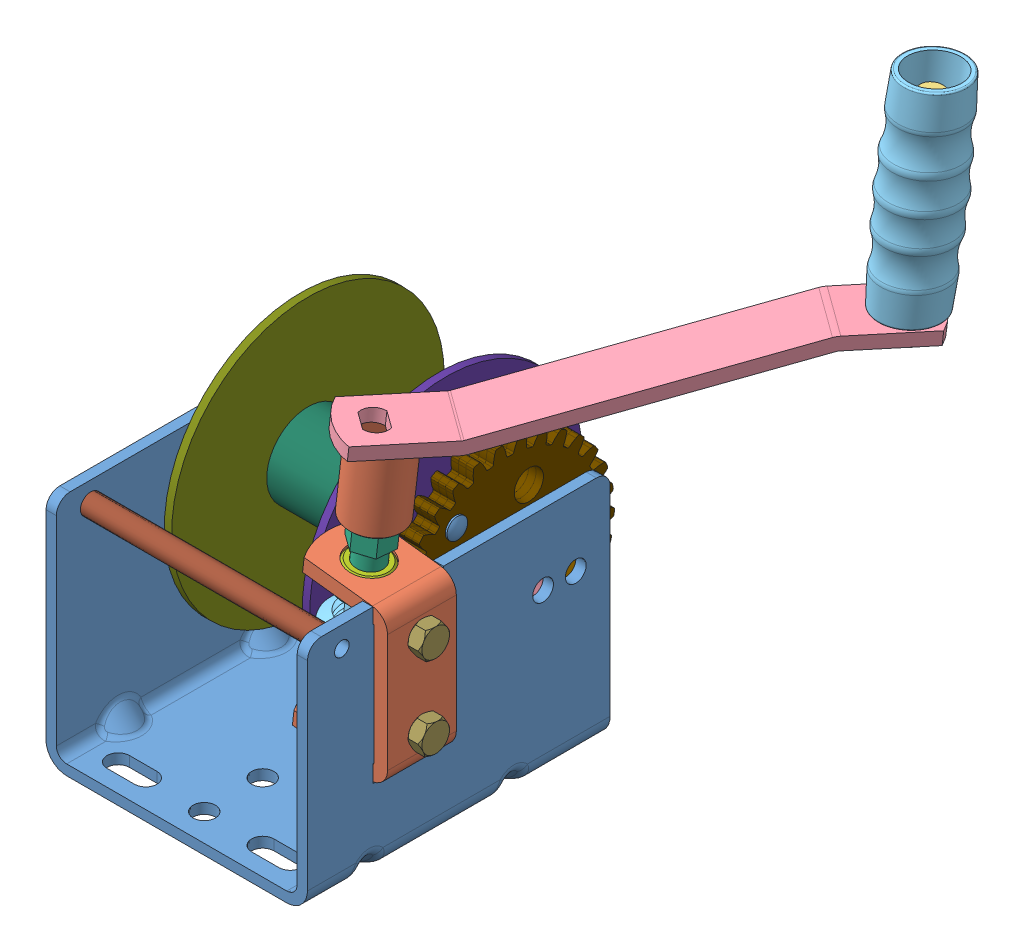
SolidWorks assembly WG1500 Hex Drive (1), configuration Predeterminado. Lengths in mm.
Overall size (251.67 346.34 225.75).
32 component instances, 24 part files, 0 mates.
Components (placement in the parent):
- 404458 Base-1: 404458 Base [Predeterminado] at origin size (120.73 107.99 139.7)
- 404457 Worm Bracket-1: 404457 Worm Bracket [Predeterminado] at (17.981 37.5729 93.2078) size (48.69 74.45 31.75)
- 204007 Drive Shaft Bottom Bushing-1: 204007 Drive Shaft Bottom Bushing [Predeterminado] at (34.0483 39.6265 93.2078) x (0.11696 0.993137 0) z (-0.289917 0.034143 -0.956443) size (10.32 23.81 23.81)
- 404439 Spacer-1: 404439 Spacer [Predeterminado] at (36.5475 60.8476 93.2078) x (-0.574047 0.067604 0.816027) z (-0.11696 -0.993137 0) size (22.23 22.23 11.05)
- 404435 Worm Gear P8-1: 404435 Worm Gear P8 [Predeterminado] at (36.5475 60.8476 93.2078) x (-0.989929 0.116582 -0.080302) z (0.11696 0.993137 0) size (33.45 33.52 39.41)
- 205186 Thrust Bearing Race-1: 205186 Thrust Bearing Race [Predeterminado] at (41.0963 99.4731 93.2078) x (0.864285 -0.101785 0.492597) z (-0.11696 -0.993137 0) size (23.81 23.81 0.79)
- 204006 Drive Shaft Bushing-1: 204006 Drive Shaft Bushing [Predeterminado] at (42.2863 109.777 93.2078) x (-0.11696 -0.993137 0) z (-0.992861 0.116927 0.023576) size (8.69 23.81 23.81)
- 205109 Flat Washer-1: 205109 Flat Washer [Predeterminado] at (41.2696 101.1436 93.2078) x (0.992132 -0.116841 -0.044969) z (-0.11696 -0.993137 0) size (23.81 23.81 1.19)
- 204489 Spring Washer-1: 204489 Spring Washer [Predeterminado] at (41.1255 99.9201 93.2078) x (0.992772 -0.116917 0.027098) z (-0.11696 -0.993137 0) size (19.05 19.05 0.41)
- 205246 Roll Pin-1: 205246 Roll Pin [Predeterminado] at (50.6614 92.7533 94.0365) x (0.122809 0.425097 -0.896778) z (-0.989929 0.116582 -0.080302) size (4.76 4.76 20.64)
- 404434 Base spacer-1: 404434 Base spacer [Predeterminado] at (0 98.425 123.825) x (0 0.855839 -0.517243) z (-1 0 0) size (9.53 9.53 111.12)
- 205235 Screw-1: 205235 Screw [Predeterminado] at (66.675 91.929 93.2078) x (0 0.999629 0.027237) z (1 0 0) size (14.68 14.68 20.87)
- 205235 Screw-2: 205235 Screw [Predeterminado] at (66.675 53.8289 93.2078) x (0 -0.575948 -0.817487) z (1 0 0) size (14.68 14.68 20.87)
- 204808 Spacer-1: 204808 Spacer [Predeterminado] at (-55.5625 75.4062 30.9626) x (0 0 -1) z (1 0 0) size (12.55 12.55 111.12)
- 204803 Lock Nut-1: 204803 Lock Nut [Predeterminado] at (-66.675 75.4062 30.9626) x (0 -0.583557 -0.812072) z (1 0 0) size (14.68 14.68 8.37)
- 304432 Reel Assembly-1: 304432 Reel Assembly [Predeterminado] at (-54.9275 75.4062 30.9626) x (1 0 0) z (0 0.563677 0.825995) size (109.98 162.45 162.45)
  - 406042 Large Reel Hub-1: 406042 Large Reel Hub [Predeterminado] at origin size (109.98 38.1 38.1)
  - 404440 Side Plate-1: 404440 Side Plate [Predeterminado] at (3.3274 0 0) x (0 -0.357166 -0.934041) z (1 0 0) size (125.81 125.81 3.43)
  - 404444 Reel Divider-1: 404444 Reel Divider [Predeterminado] at (67.0179 0 0) x (0 0.239819 -0.970818) z (1 0 0) size (125.81 125.81 3.43)
  - 304395 Tooth Gear Assembly-1: 304395 Tooth Gear Assembly [Predeterminado] at (87.9094 0 0) x (0 0.960662 -0.277719) z (1 0 0) size (99.67 100.01 13.42)
    - 404443 30T Gear-1: 404443 30T Gear [Predeterminado] at origin size (99.67 100.01 3.42)
    - 404443 30T Gear-2: 404443 30T Gear [Predeterminado] at (0 0 3.4163) size (99.67 100.01 3.42)
    - 404443 30T Gear-3: 404443 30T Gear [Predeterminado] at (0 0 6.8326) size (99.67 100.01 3.42)
    - 206078 Rivit-1: 206078 Rivit [Predeterminado] at (0 36.5125 12.6289) x (0 0 -1) z (-0.029007 -0.999579 0) size (13.42 9.53 9.53)
    - 206078 Rivit-2: 206078 Rivit [Predeterminado] at (31.6208 -18.2563 12.6289) x (0 0 -1) z (0.972835 0.231501 0) size (13.42 9.53 9.53)
    - 206078 Rivit-3: 206078 Rivit [Predeterminado] at (-31.6208 -18.2563 12.6289) x (0 0 -1) z (-0.172822 0.984953 0) size (13.42 9.53 9.53)
- 306132 Hex Handle-1: 306132 Hex Handle [Predeterminado] at (44.5344 128.6668 93.2078) x (0.564031 -0.066425 -0.823077) z (0.817428 -0.096267 0.567929) size (205.72 178.9 28.5)
  - 206596 Socket-1: 206596 Socket [Predeterminado] at origin size (25.4 34.44 25.4)
  - 204005 Crank Handle Pin-1: 204005 Crank Handle Pin [Predeterminado] at (171.45 67.7736 0) x (0 1 0) z (-0.529748 0 0.848155) size (101.2 19.05 19.05)
  - 404234 7 Handle-1: 404234 7 Handle [Predeterminado] at (-17.4625 34.4361 0) size (201.61 42.86 25.4)
  - 204004 Handle Sleeve-1: 204004 Handle Sleeve [Predeterminado] at (171.45 178.8986 0) x (0 -1 0) z (0 0 1) size (101.61 33.06 28.5)
- 406102 WG Hex Shaft-1: 406102 WG Hex Shaft [Predeterminado] at (43.2302 117.5927 93.2078) x (0.989929 -0.116582 0.080302) z (0.11696 0.993137 0) size (15.88 18.33 110.23)
